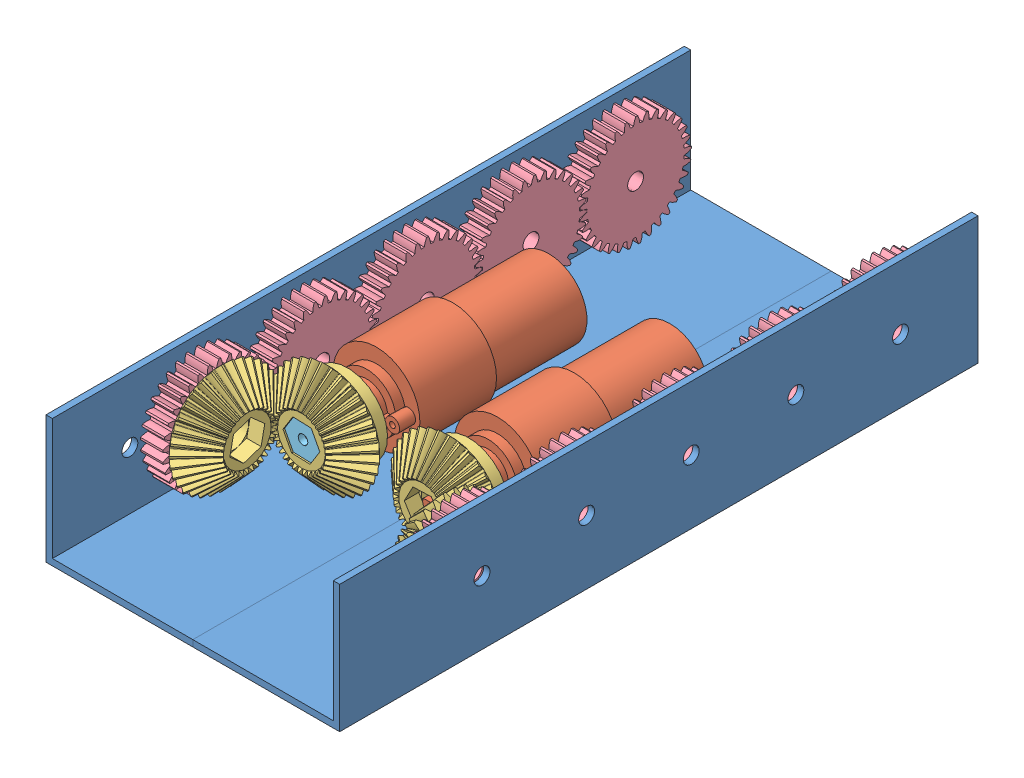
SolidWorks assembly EnsamblePrueba, configuration Predeterminado. Lengths in mm.
Overall size (92 49.45 200).
19 component instances, 5 part files, 26 mates.
Components (placement in the parent):
- 001 - Chassis-1: 001 - Chassis [Predeterminado] at origin size (46 40 200)
- 001 - motor-1: 001 - motor [Predeterminado] x (1 0 0) z (0 -1 0) size (27.3 75 27.3)
- engranaje M1 dientes 33 diametro 30-3: engranaje M1 dientes 33 diametro 30 [pinon M1 dientes 33 diametro 30] at (0 0 37.9492) x (0 0 1) z (0.531464 -0.847081 0) size (15.81 34.43 34.47)
- engranaje M1 dientes 33 diametro 30-2: engranaje M1 dientes 33 diametro 30 [pinon M1 dientes 33 diametro 30] at (17.5508 0 55.4) x (-1 0 0) z (0 -0.979258 0.202615) size (15.81 34.43 34.47)
- ISO -  1M 33T 20PA 12FW llantas-16: ISO -  1M 33T 20PA 12FW llantas [ISO -  1M 33T 20PA 12FW] at (17.5508 0 55.4) x (1 0 0) z (0 -0.022608 -0.999744) size (7 34.95 34.98)
- ISO -  1M 33T 20PA 12FW llantas-19: ISO -  1M 33T 20PA 12FW llantas [ISO -  1M 33T 20PA 12FW] at (18 0 22.62) x (1 0 0) z (0 0.799774 0.600302) size (7 34.95 34.98)
- ISO -  1M 33T 20PA 12FW llantas-20: ISO -  1M 33T 20PA 12FW llantas [ISO -  1M 33T 20PA 12FW] at (18 0 -10.16) x (1 0 0) z (0 -0.706306 -0.707907) size (7 34.95 34.98)
- ISO -  1M 33T 20PA 12FW llantas-17: ISO -  1M 33T 20PA 12FW llantas [ISO -  1M 33T 20PA 12FW] at (18 0 -42.94) x (1 0 0) z (0 0.305644 -0.952146) size (7 34.95 34.98)
- ISO -  1M 33T 20PA 12FW llantas-18: ISO -  1M 33T 20PA 12FW llantas [ISO -  1M 33T 20PA 12FW] at (18 0 -75.72) x (1 0 0) z (0 -0.210462 -0.977602) size (7 34.95 34.98)
- ISO -  1M 33T 20PA 12FW llantas-21: ISO -  1M 33T 20PA 12FW llantas [ISO -  1M 33T 20PA 12FW] at (-56 0 -10.16) x (-1 0 0) z (0 0.706306 0.707907) size (7 34.95 34.98)
- 001 - motor-2: 001 - motor [Predeterminado] at (-38 0 0) x (1 0 0) z (0 -1 0) size (27.3 75 27.3)
- 001 - Chassis-2: 001 - Chassis [Predeterminado] at (-38 0 0) x (-1 0 0) z (0 0 -1) size (46 40 200)
- ISO -  1M 33T 20PA 12FW llantas-22: ISO -  1M 33T 20PA 12FW llantas [ISO -  1M 33T 20PA 12FW] at (-55.5508 0 55.4) x (-1 0 0) z (0 0.022608 0.999744) size (7 34.95 34.98)
- engranaje M1 dientes 33 diametro 30-4: engranaje M1 dientes 33 diametro 30 [pinon M1 dientes 33 diametro 30] at (-38 0 37.9492) x (0 0 1) z (0.531464 0.847081 0) size (15.81 34.43 34.47)
- engranaje M1 dientes 33 diametro 30-5: engranaje M1 dientes 33 diametro 30 [pinon M1 dientes 33 diametro 30] at (-55.5508 0 55.4) x (1 0 0) z (0 0.979258 -0.202615) size (15.81 34.43 34.47)
- ISO -  1M 33T 20PA 12FW llantas-23: ISO -  1M 33T 20PA 12FW llantas [ISO -  1M 33T 20PA 12FW] at (-56 0 22.62) x (-1 0 0) z (0 -0.799774 -0.600302) size (7 34.95 34.98)
- ISO -  1M 33T 20PA 12FW llantas-24: ISO -  1M 33T 20PA 12FW llantas [ISO -  1M 33T 20PA 12FW] at (-56 0 -42.94) x (-1 0 0) z (0 -0.305644 0.952146) size (7 34.95 34.98)
- ISO -  1M 33T 20PA 12FW llantas-25: ISO -  1M 33T 20PA 12FW llantas [ISO -  1M 33T 20PA 12FW] at (-56 0 -75.72) x (-1 0 0) z (0 0.210462 0.977602) size (7 34.95 34.98)
- acople Piñon Motor-1: acople Piñon Motor [Predeterminado] at (-38 0 42.4749) x (0.999326 -0.036721 0) z (0 0 1) size (11.55 10 17)
Mates (geometry in assembly coordinates):
- Coincidente1: coordinate: point of 001 - Chassis-1
- Coincidente3: coincident anti-aligned: plane of 001 - motor-1 through (0 0 0) normal (0 -1 0)
- Coincidente5: coincident aligned: plane of 001 - motor-1 through (0 0 0) normal (0 0 1)
- Coincidente6: coincident aligned: plane of 001 - motor-1 through (0 0 0) normal (1 0 0)
- Distancia1: distance = 2 mm anti-aligned: plane of 001 - Chassis-1 through (25 -18 100) normal (-1 0 0); plane of straight bevel pinion_iso-2 through (23 0 55.4) normal (1 0 0)
- Concéntrica1: concentric: cylinder of 001 - motor-1 through (0 0 65.6872) axis (0 0 1) radius 2.5; cylinder of engranaje M1 dientes 33 diametro 30-3 through (0 0 60.9492) axis (0 0 -1) radius 2.5
- Distancia2: distance = 2 mm anti-aligned: plane of straight bevel pinion_iso-1 through (0 0 32.5) normal (0 0 -1); plane of 001 - motor-1 through (0 0 30.5) normal (0 0 1)
- Concéntrica2: concentric: cylinder of 001 - Chassis-1 through (17 0 55.4) axis (1 0 0) radius 2.5; cylinder of engranaje M1 dientes 33 diametro 30-2 through (-5.4492 0 55.4) axis (1 0 0) radius 2.5
- Relación de posición de engranaje1: gear = 15.0085 : 15.0085 mm: circle of straight bevel pinion_iso-2; circle of straight bevel pinion_iso-1
- Concéntrica3: concentric: cylinder of engranaje M1 dientes 33 diametro 30-2 through (-5.4492 0 55.4) axis (1 0 0) radius 2.5; cylinder of ISO -  1M 33T 20PA 12FW llantas-16 through (67.5509 0 55.4) axis (-1 0 0) radius 2.5
- Coincidente13: coincident anti-aligned: plane of engranaje M1 dientes 33 diametro 30-2 through (17.5508 0 55.4) normal (1 0 0); plane of ISO -  1M 33T 20PA 12FW llantas-16 through (17.5508 0 55.4) normal (-1 0 0)
- Concéntrica4: concentric anti-aligned: cylinder of 001 - Chassis-1 through (17 0 22.62) axis (1 0 0) radius 2.5; cylinder of ISO -  1M 33T 20PA 12FW llantas-19 through (68.0001 0 22.62) axis (-1 0 0) radius 2.5
- Coincidente14: coincident anti-aligned: plane of 001 - Chassis-1 through (25 -18 100) normal (-1 0 0); plane of ISO -  1M 33T 20PA 12FW llantas-19 through (25 0 22.62) normal (1 0 0)
- Relación de posición de engranaje2: gear = 35 : 35 mm: circle of ISO -  1M 33T 20PA 12FW llantas-2; circle of ISO -  1M 33T 20PA 12FW llantas-1
- Coincidente17: coincident anti-aligned: plane of 001 - Chassis-1 through (25 -18 100) normal (-1 0 0); plane of ISO -  1M 33T 20PA 12FW llantas-20 through (25 0 -10.16) normal (1 0 0)
- Concéntrica5: concentric anti-aligned: cylinder of 001 - Chassis-1 through (17 0 -10.16) axis (1 0 0) radius 2.5; cylinder of ISO -  1M 33T 20PA 12FW llantas-20 through (68.0001 0 -10.16) axis (-1 0 0) radius 2.5
- Relación de posición de engranaje3: gear = 35 : 35 mm: circle of ISO -  1M 33T 20PA 12FW llantas-2; circle of ISO -  1M 33T 20PA 12FW llantas-3
- Coincidente19: coincident anti-aligned: plane of 001 - Chassis-1 through (25 -18 100) normal (-1 0 0); plane of ISO -  1M 33T 20PA 12FW llantas-17 through (25 0 -42.94) normal (1 0 0)
- Concéntrica6: concentric anti-aligned: cylinder of 001 - Chassis-1 through (17 0 -42.94) axis (1 0 0) radius 2.5; cylinder of ISO -  1M 33T 20PA 12FW llantas-17 through (68.0001 0 -42.94) axis (-1 0 0) radius 2.5
- Relación de posición de engranaje4: gear = 35 : 35 mm: circle of ISO -  1M 33T 20PA 12FW llantas-4; circle of ISO -  1M 33T 20PA 12FW llantas-3
- Concéntrica7: concentric anti-aligned: cylinder of 001 - Chassis-1 through (17 0 -75.72) axis (1 0 0) radius 2.5; cylinder of ISO -  1M 33T 20PA 12FW llantas-18 through (68.0001 0 -75.72) axis (-1 0 0) radius 2.5
- Coincidente21: coincident anti-aligned: plane of 001 - Chassis-1 through (25 -18 100) normal (-1 0 0); plane of ISO -  1M 33T 20PA 12FW llantas-18 through (25 0 -75.72) normal (1 0 0)
- Relación de posición de engranaje5: gear = 35 : 35 mm: circle of ISO -  1M 33T 20PA 12FW llantas-5; circle of ISO -  1M 33T 20PA 12FW llantas-4
- Concéntrica8: concentric aligned: cylinder of 001 - motor-2 through (-38 0 65.6872) axis (0 0 1) radius 2.5; cylinder of acople Piñon Motor-1 through (-38 0 29.4749) axis (0 0 1) radius 2.5
- Coincidente22: coincident anti-aligned: plane of engranaje M1 dientes 33 diametro 30-4 through (-38 0 42.4749) normal (0 0 1); plane of acople Piñon Motor-1 through (-38 0 42.4749) normal (0 0 -1)
- Coincidente23: coincident anti-aligned: plane of engranaje M1 dientes 33 diametro 30-4 through (-41.0684 -4.8906 42.4749) normal (0.036721 0.999326 0); plane of acople Piñon Motor-1 through (-41.0684 -4.8906 46.4749) normal (-0.036721 -0.999326 0)
